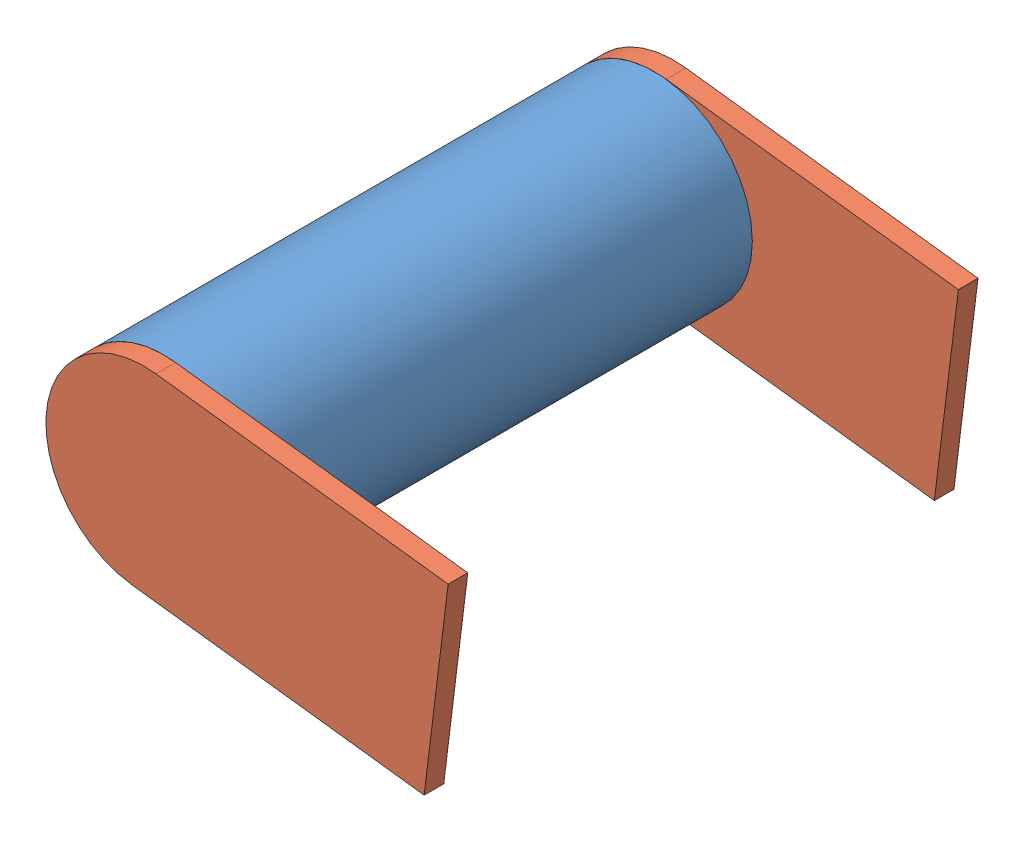
SolidWorks assembly poigné, configuration Défaut. Lengths in mm.
Overall size (42.15 24.75 54).
3 component instances, 2 part files, 6 mates.
Components (placement in the parent):
- Pièce3-1: Pièce3 [Défaut] at (-9.8156 -1.3824 -22.5) size (20 20 50)
- Pièce4-1: Pièce4 [Défaut] at (19.9586 -5.0565 29.5) x (-0.122472 -0.992472 0) z (0 0 -1) size (20 40 2)
- Pièce4-3: Pièce4 [Défaut] at (19.9586 -5.0565 -24.5) x (0.122472 0.992472 0) z (0 0 1) size (20 40 2)
Mates (geometry in assembly coordinates):
- Coïncidente3: coincident: plane of Pièce3-1 through (-9.8156 -1.3824 27.5) normal (0 0 1); plane of Pièce4-1 through (-9.8156 -1.3824 27.5) normal (0 0 -1)
- Coïncidente4: coincident: circle of Pièce3-1; circle of Pièce4-1
- Verrouiller2: lock: unknown of Pièce3-1; unknown of Pièce4-1
- Coïncidente5: coincident anti-aligned: plane of Pièce3-1 through (-9.8156 -1.3824 -22.5) normal (0 0 -1); plane of Pièce4-3 through (-9.8156 -1.3824 -22.5) normal (0 0 1)
- Coïncidente6: coincident anti-aligned: circle of Pièce3-1; circle of Pièce4-3
- Coïncidente7: coincident aligned: plane of Pièce4-1 through (-11.0403 -11.3071 27.5) normal (-0.122472 -0.992472 0); plane of Pièce4-3 through (18.7338 -14.9812 -22.5) normal (-0.122472 -0.992472 0)
